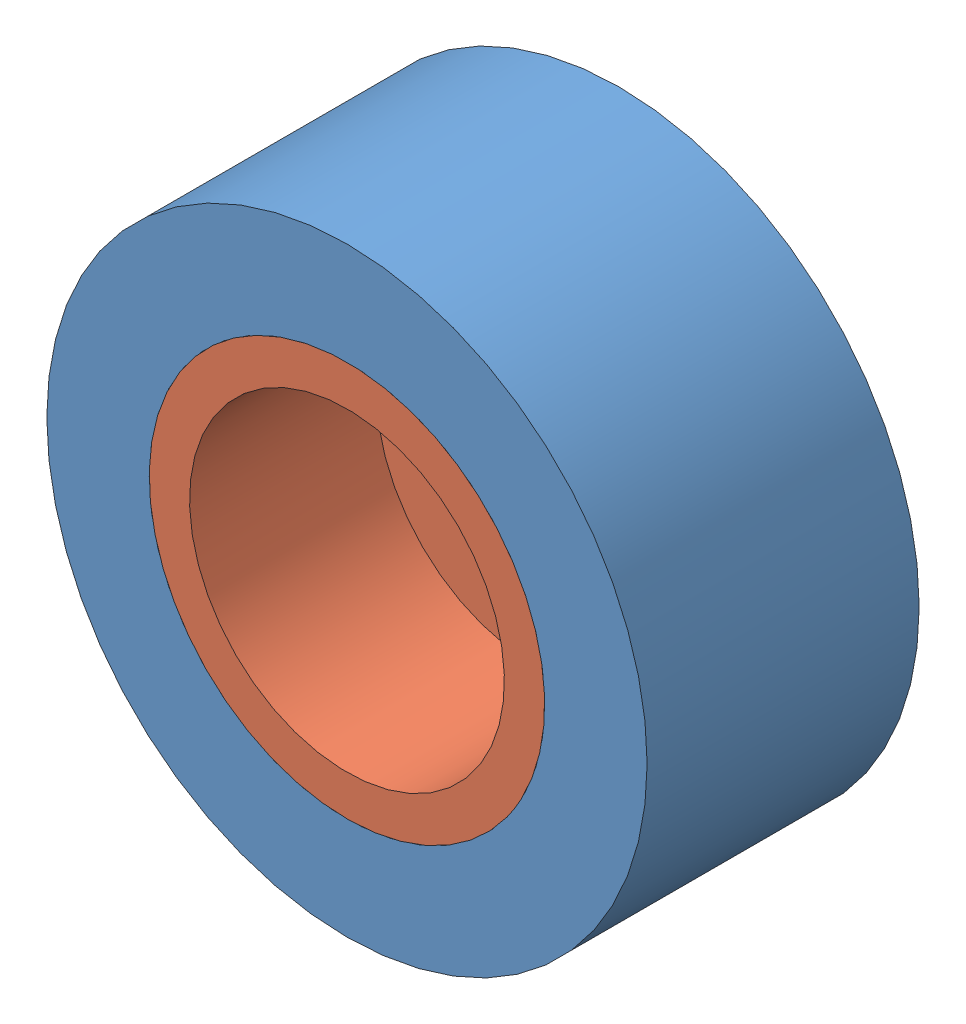
SolidWorks assembly koło_solarbotics, configuration Domyślna. Lengths in mm.
Overall size (28.6 28.6 18.12).
2 component instances, 2 part files, 3 mates.
Components (placement in the parent):
- opona solarbotics-1: opona solarbotics [Domyślna] at (-8.1051 -0.3184 28.6) size (28.6 28.6 12.96)
- felga_solarbotics-1: felga_solarbotics [Domyślna] at (-8.1051 -0.3184 28.44) x (0.847028 -0.531548 0) z (0 0 1) size (20.38 20.38 18.12)
Mates (geometry in assembly coordinates):
- Koncentryczne1: concentric aligned: cylinder of opona solarbotics-1 through (-8.1051 -0.3184 41.56) axis (0 0 -1) radius 14.3; cylinder of felga_solarbotics-1 through (-8.1051 -0.3184 36.46) axis (0 0 -1) radius 10.19
- Zablokuj1: lock: unknown of opona solarbotics-1; unknown of felga_solarbotics-1
- Wspólnie5: coincident anti-aligned: plane of opona solarbotics-1 through (-8.1051 -0.3184 33.7) normal (0 0 1); plane of felga_solarbotics-1 through (-8.1051 -0.3184 33.7) normal (0 0 -1)
